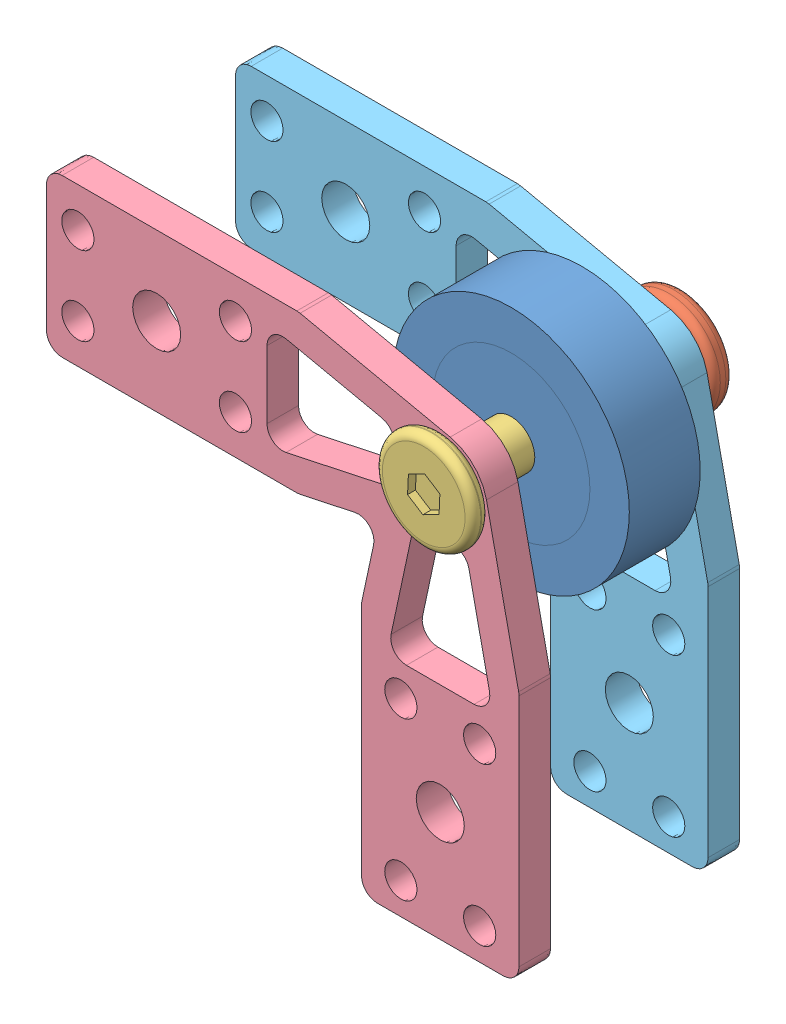
SolidWorks assembly 导轮, configuration 默认. Lengths in mm.
Overall size (65 65 32.8).
5 component instances, 5 part files, 10 mates.
Components (placement in the parent):
- DP_导轮_1-1: DP_导轮_1 [默认] at origin size (30 30 9)
- DP_对锁螺母M6X8 -1: DP_对锁螺母M6X8  [默认] at (0 0 -17.2) x (0 0 1) z (-0.999978 0.006658 0) size (12.7 13.1 13.1)
- DP_对锁螺栓M6 - 副本-1: DP_对锁螺栓M6 - 副本 [默认] at (0 0 15.6) x (0 0 -1) z (0.842212 -0.539147 0) size (27.1 12.5 12.5)
- DP_保险杠导轮安装板_1.0-1: DP_保险杠导轮安装板_1.0 [上] at (0 0 9.5) size (60 60 4)
- DP_保险杠导轮安装板_1.0 - 2-1: DP_保险杠导轮安装板_1.0 - 2 [上] at (0 0 -14.5) size (60 60 4)
Mates (geometry in assembly coordinates):
- 同心1: concentric aligned: cylinder of DP_导轮_1-1 through (0 0 4.5) axis (0 0 -1) radius 3; cylinder of DP_对锁螺母M6X8 -1 through (0 0 -17.2) axis (0 0 -1) radius 3.95
- 距离1: distance = 28 mm anti-aligned: plane of DP_对锁螺栓M6 - 副本-1 through (3.3697 5.2638 13.5) normal (0 0 -1); plane of DP_对锁螺母M6X8 -1 through (0.0436 6.5499 -14.5) normal (0 0 1)
- 同心2: concentric aligned: cylinder of DP_导轮_1-1 through (0 0 4.5) axis (0 0 -1) radius 3; cylinder of DP_对锁螺栓M6 - 副本-1 through (0 0 -11.5) axis (0 0 -1) radius 3
- 重合3: coincident anti-aligned: plane of DP_导轮_1-1 through (0 0 -4.5) normal (0 0 -1); plane of DP_对锁螺母M6X8 -1 through (0.0263 3.9499 -4.5) normal (0 0 1)
- 同心3: concentric aligned: circle of DP_对锁螺母M6X8 -1; cylinder of DP_保险杠导轮安装板_1.0-1 through (-1.9457 -0.8296 -19.3277) axis (0 0 1) radius 3.05
- 同心4: concentric anti-aligned: cylinder of DP_对锁螺母M6X8 -1 through (0 0 -17.2) axis (0 0 -1) radius 3.95; cylinder of DP_保险杠导轮安装板_1.0 - 2-1 through (0 0 -21.5) axis (0 0 1) radius 4.1
- 重合4: coincident anti-aligned: plane of DP_对锁螺母M6X8 -1 through (0.0436 6.5499 -14.5) normal (0 0 1); plane of DP_保险杠导轮安装板_1.0 - 2-1 through (0 0 -14.5) normal (0 0 -1)
- 重合5: coincident anti-aligned: plane of DP_对锁螺栓M6 - 副本-1 through (3.3697 5.2638 13.5) normal (0 0 -1); plane of DP_保险杠导轮安装板_1.0-1 through (-1.9457 -0.8296 -8.3277) normal (0 0 1)
- 重合6: coincident anti-aligned: plane of DP_对锁螺母M6X8 -1 through (0.0436 6.5499 -14.5) normal (0 0 1); plane of DP_保险杠导轮安装板_1.0 - 2-1 through (0 0 -14.5) normal (0 0 -1)
- 重合7: coincident aligned: plane of DP_保险杠导轮安装板_1.0-1 through (-50 10 12.5) normal (0 1 0); plane of DP_保险杠导轮安装板_1.0 - 2-1 through (-50 10 -11.5) normal (0 1 0)
